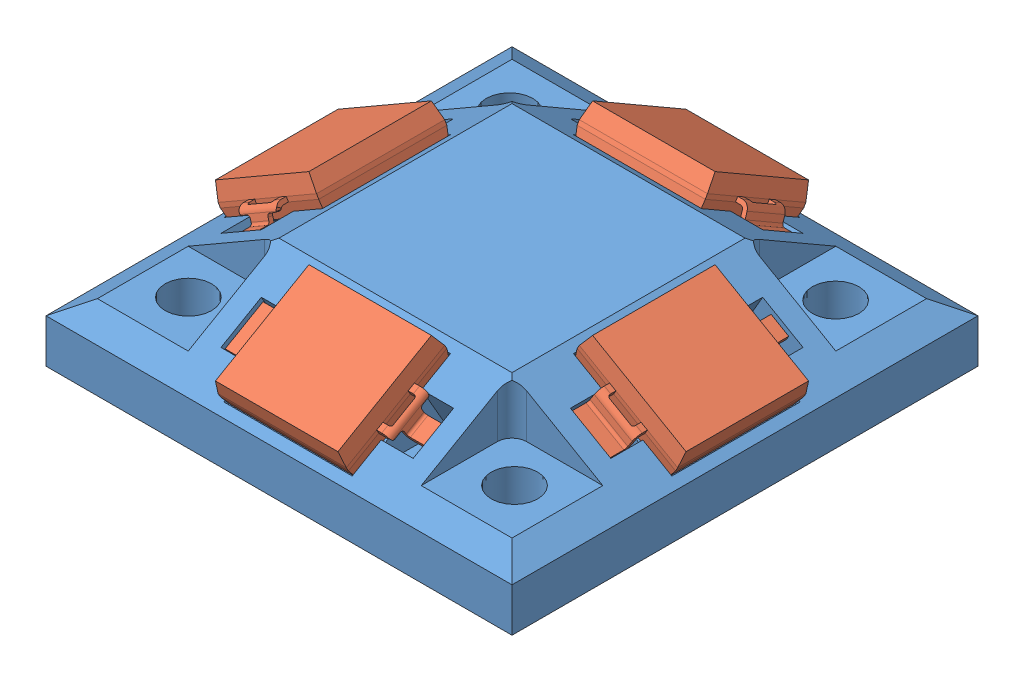
SolidWorks assembly New Pryamid with Mounting Slots Prototype (Full Body), configuration Default. Lengths in mm.
Overall size (16.33 4.45 16.33).
5 component instances, 2 part files, 14 mates.
Components (placement in the parent):
- Sun Sensor Mount #2 Complete with Holes Prototype-1: Sun Sensor Mount #2 Complete with Holes Prototype [Default] at (-27.8384 3.5231 13.3155) size (16 3.81 16)
- SFH_2430_100414_geometry-1: SFH_2430_100414_geometry [Default] at (-33.9634 2.5849 13.3155) x (-0.866025 -0.5 0) z (0 0 -1) size (3.9 1.2 6.5)
- SFH_2430_100414_geometry-4: SFH_2430_100414_geometry [Default] at (-21.7134 2.5849 13.3155) x (0.866025 -0.5 0) z (0 0 1) size (3.9 1.2 6.5)
- SFH_2430_100414_geometry-2: SFH_2430_100414_geometry [Default] at (-27.8384 2.5849 7.1905) x (0 -0.5 -0.866025) z (1 0 0) size (3.9 1.2 6.5)
- SFH_2430_100414_geometry-3: SFH_2430_100414_geometry [Default] at (-27.8384 2.5849 19.4405) x (0 -0.5 0.866025) z (-1 0 0) size (3.9 1.2 6.5)
Mates (geometry in assembly coordinates):
- Coincident2: coincident anti-aligned: plane of Sun Sensor Mount #2 Complete with Holes Prototype-1 through (-26.9384 5.082 13.3155) normal (0.5 0.866025 0); plane of SFH_2430_100414_geometry-4 through (-21.9384 2.1952 13.3155) normal (-0.5 -0.866025 0)
- Coincident5: coincident anti-aligned: plane of Sun Sensor Mount #2 Complete with Holes Prototype-1 through (-23.6272 3.1702 15.5155) normal (0 0 -1); plane of SFH_2430_100414_geometry-4 through (-23.3272 3.6898 15.5155) normal (0 0 1)
- Coincident9: coincident anti-aligned: plane of Sun Sensor Mount #2 Complete with Holes Prototype-1 through (-30.0384 3.1702 17.5267) normal (1 0 0); plane of SFH_2430_100414_geometry-3 through (-30.0384 3.6898 17.8267) normal (-1 0 0)
- Parallel5: parallel anti-aligned: line of Sun Sensor Mount #2 Complete with Holes Prototype-1 through (-25.6384 3.3434 9.0042) axis (-1 0 0); line of SFH_2430_100414_geometry-2 through (-29.9414 2.2646 5.2357) axis (1 0 0)
- Coincident14: coincident anti-aligned: plane of Sun Sensor Mount #2 Complete with Holes Prototype-1 through (-25.6384 3.1702 9.1042) normal (-1 0 0); plane of SFH_2430_100414_geometry-2 through (-25.6384 3.6898 8.8042) normal (1 0 0)
- Coincident15: coincident anti-aligned: plane of Sun Sensor Mount #2 Complete with Holes Prototype-1 through (-25.6384 3.1702 9.1042) normal (0 -0.5 -0.866025); plane of SFH_2430_100414_geometry-2 through (-25.6384 3.6898 8.8042) normal (0 0.5 0.866025)
- Coincident21: coincident anti-aligned: plane of Sun Sensor Mount #2 Complete with Holes Prototype-1 through (-30.0384 3.1702 17.5267) normal (0 -0.5 0.866025); plane of SFH_2430_100414_geometry-3 through (-30.0384 3.6898 17.8267) normal (0 0.5 -0.866025)
- Coincident22: coincident anti-aligned: plane of Sun Sensor Mount #2 Complete with Holes Prototype-1 through (-25.6384 3.1702 17.5267) normal (-1 0 0); plane of SFH_2430_100414_geometry-3 through (-25.6384 3.6898 17.8267) normal (1 0 0)
- Coincident23: coincident anti-aligned: plane of Sun Sensor Mount #2 Complete with Holes Prototype-1 through (-27.8384 5.082 14.2155) normal (0 0.866025 0.5); plane of SFH_2430_100414_geometry-3 through (-27.8384 2.1952 19.2155) normal (0 -0.866025 -0.5)
- Coincident24: coincident anti-aligned: plane of Sun Sensor Mount #2 Complete with Holes Prototype-1 through (-28.7384 5.082 13.3155) normal (-0.5 0.866025 0); plane of SFH_2430_100414_geometry-1 through (-33.7384 2.1952 13.3155) normal (0.5 -0.866025 0)
- Coincident25: coincident anti-aligned: plane of Sun Sensor Mount #2 Complete with Holes Prototype-1 through (-32.0497 3.1702 15.5155) normal (-0.866025 -0.5 0); plane of SFH_2430_100414_geometry-1 through (-32.3497 3.6898 11.1155) normal (0.866025 0.5 0)
- Coincident26: coincident anti-aligned: plane of Sun Sensor Mount #2 Complete with Holes Prototype-1 through (-32.0497 3.1702 15.5155) normal (0 0 -1); plane of SFH_2430_100414_geometry-1 through (-32.3497 3.6898 15.5155) normal (0 0 1)
- Coincident27: coincident anti-aligned: plane of Sun Sensor Mount #2 Complete with Holes Prototype-1 through (-23.6272 3.1702 11.1155) normal (0.866025 -0.5 0); plane of SFH_2430_100414_geometry-4 through (-23.3272 3.6898 15.5155) normal (-0.866025 0.5 0)
- Coincident28: coincident anti-aligned: plane of Sun Sensor Mount #2 Complete with Holes Prototype-1 through (-27.8384 5.082 12.4155) normal (0 0.866025 -0.5); plane of SFH_2430_100414_geometry-2 through (-27.8384 2.1952 7.4155) normal (0 -0.866025 0.5)
